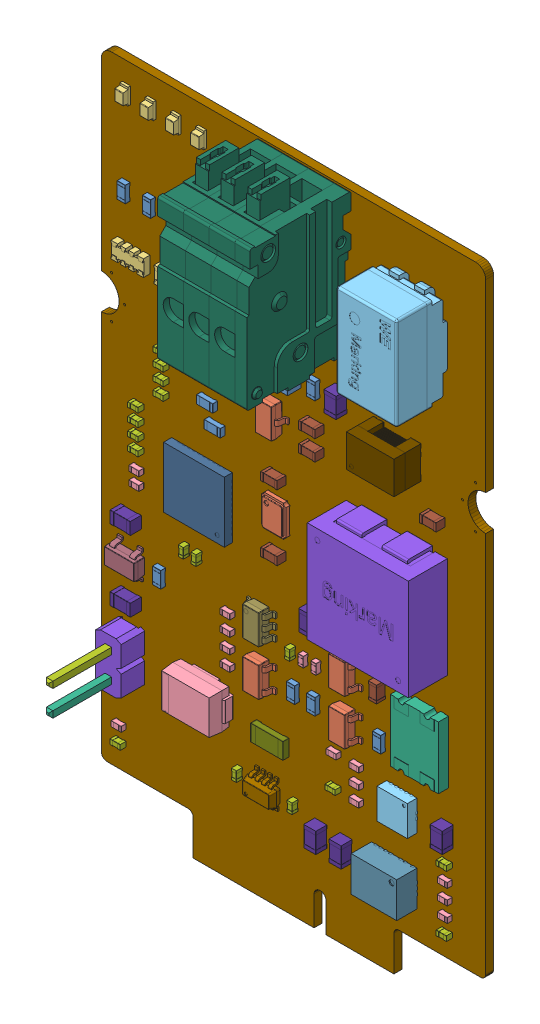
SolidWorks assembly spe-sink, configuration Default. Lengths in mm.
Overall size (38 67.08 13.5).
184 component instances, 27 part files, 0 mates.
Components (placement in the parent):
- spe-sink.step-1: spe-sink.step [Default] at origin size (38 67.08 13.5)
  - RESC1608X50.step-1: RESC1608X50.step [Default] at (121.25 -57.5 0.83) x (0 -1 0) z (0 0 1) size (1.6 0.8 0.5)
    - COMPOUND.step-1: COMPOUND.step [Default] at origin size (1.6 0.8 0.5)
  - RESC1608X50.step-2: RESC1608X50.step [Default] at (105 -50 0.83) x (0 -1 0) z (0 0 1) size (1.6 0.8 0.5)
    - COMPOUND.step-1: COMPOUND.step [Default] at origin size (1.6 0.8 0.5)
  - RESC1608X50.step-3: RESC1608X50.step [Default] at (107.5 -50 0.83) x (0 -1 0) z (0 0 1) size (1.6 0.8 0.5)
    - COMPOUND.step-1: COMPOUND.step [Default] at origin size (1.6 0.8 0.5)
  - SOT95P240X110-3L16.step-1: SOT95P240X110-3L16.step [Default] at (116 -84.5 0.83) size (2.84 3.01 1.19)
    - COMPOUND-0.step-1: COMPOUND-0.step [Default] at origin size (2.84 3.01 1.19)
  - R_Array_Concave_4x060.step-1: R_Array_Concave_4x060.step [Default] at (103.25 -55.25 0.83) x (1 0 0) z (0 -1 0) size (3.2 0.65 1.6)
    - SOLID.step-1: SOLID.step [Default] at origin size (3.2 0.65 1.6)
  - RESC1005X40.step-1: RESC1005X40.step [Default] at (112.75 -85.5 0.83) x (-1 0 0) z (0 0 1) size (1 0.5 0.5)
    - COMPOUND-1.step-1: COMPOUND-1.step [Default] at origin size (1 0.5 0.5)
  - WE-SL2.step-1: WE-SL2.step [Default] at (131.25 -47.5 0.83) x (0 -1 0) z (0 0 1) size (9.2 6 5)
    - COMPOUND-2.step-1: COMPOUND-2.step [Default] at origin size (9.2 6 5)
  - RESC1005X40.step-2: RESC1005X40.step [Default] at (134.25 -94.75 0.83) size (1 0.5 0.5)
    - COMPOUND-1.step-1: COMPOUND-1.step [Default] at origin size (1 0.5 0.5)
  - CD-HD2xL.step-1: CD-HD2xL.step [Default] at (132 -82.25 1.33) x (0 1 0) z (-1 0 0) size (6.15 1.07 4.75)
    - COMPOUND-3.step-1: COMPOUND-3.step [Default] at origin size (6.15 1.07 4.75)
  - RESC1005X40.step-3: RESC1005X40.step [Default] at (111.975 -61.75 0.83) x (0 -1 0) z (0 0 1) size (1 0.5 0.5)
    - COMPOUND-1.step-1: COMPOUND-1.step [Default] at origin size (1 0.5 0.5)
  - CAPC1005X60.step-1: CAPC1005X60.step [Default] at (106.25 -65.5 0.83) x (-1 0 0) z (0 0 1) size (1 0.5 0.6)
    - COMPOUND-4.step-1: COMPOUND-4.step [Default] at origin size (1 0.5 0.6)
  - RESC1608X50.step-4: RESC1608X50.step [Default] at (119.25 -84.5 0.83) x (0 -1 0) z (0 0 1) size (1.6 0.8 0.5)
    - COMPOUND.step-1: COMPOUND.step [Default] at origin size (1.6 0.8 0.5)
  - WE-MCRI-1040.step-1: WE-MCRI-1040.step [Default] at (129.25 -70.75 0.83) x (0 1 0) z (0 0 1) size (10.7 10 4.12)
    - COMPOUND-5.step-1: COMPOUND-5.step [Default] at origin size (10.7 10 4.12)
  - RESC1005X40.step-4: RESC1005X40.step [Default] at (103.75 -73.25 0.83) size (1 0.5 0.5)
    - COMPOUND-1.step-1: COMPOUND-1.step [Default] at origin size (1 0.5 0.5)
  - SOT23_8P65_280X145L45X30.step-1: SOT23_8P65_280X145L45X30.step [Default] at (116.5 -94.25 0.83) size (2.94 2.8 1.2)
    - COMPOUND-6.step-1: COMPOUND-6.step [Default] at origin size (2.94 2.8 1.2)
  - CAPC1005X60.step-2: CAPC1005X60.step [Default] at (106.25 -64.25 0.83) x (-1 0 0) z (0 0 1) size (1 0.5 0.6)
    - COMPOUND-4.step-1: COMPOUND-4.step [Default] at origin size (1 0.5 0.6)
  - QFN50P600X600X100-40.step-1: QFN50P600X600X100-40.step [Default] at (110 -72 0.83) x (0 1 0) z (1 0 0) size (6 0.8 6)
    - COMPOUND-7.step-1: COMPOUND-7.step [Default] at origin size (6 0.8 6)
  - CAPC1005X60.step-3: CAPC1005X60.step [Default] at (103.75 -69 0.83) x (-1 0 0) z (0 0 1) size (1 0.5 0.6)
    - COMPOUND-4.step-1: COMPOUND-4.step [Default] at origin size (1 0.5 0.6)
  - RESC1608X50.step-5: RESC1608X50.step [Default] at (111.5 -65.75 0.83) x (-1 0 0) z (0 0 1) size (1.6 0.8 0.5)
    - COMPOUND.step-1: COMPOUND.step [Default] at origin size (1.6 0.8 0.5)
  - CAPC1608X90.step-1: CAPC1608X90.step [Default] at (121.25 -60.75 0.83) x (-1 0 0) z (0 0 1) size (1.6 0.8 0.9)
    - COMPOUND-8.step-1: COMPOUND-8.step [Default] at origin size (1.6 0.8 0.9)
  - RESC1005X40.step-5: RESC1005X40.step [Default] at (112.75 -82.5 0.83) x (-1 0 0) z (0 0 1) size (1 0.5 0.5)
    - COMPOUND-1.step-1: COMPOUND-1.step [Default] at origin size (1 0.5 0.5)
  - RESC1005X40.step-6: RESC1005X40.step [Default] at (120.25 -81.25 0.83) x (0 -1 0) z (0 0 1) size (1 0.5 0.5)
    - COMPOUND-1.step-1: COMPOUND-1.step [Default] at origin size (1 0.5 0.5)
  - CAPC1005X60.step-4: CAPC1005X60.step [Default] at (106.25 -61.75 0.83) x (-1 0 0) z (0 0 1) size (1 0.5 0.6)
    - COMPOUND-4.step-1: COMPOUND-4.step [Default] at origin size (1 0.5 0.6)
  - CAPC1608X90.step-2: CAPC1608X90.step [Default] at (117.5 -67 0.83) size (1.6 0.8 0.9)
    - COMPOUND-8.step-1: COMPOUND-8.step [Default] at origin size (1.6 0.8 0.9)
  - SOT95P240X110-6L16.step-1: SOT95P240X110-6L16.step [Default] at (116 -80 0.83) x (-1 0 0) z (0 0 1) size (2.85 3.01 1.19)
    - COMPOUND-9.step-1: COMPOUND-9.step [Default] at origin size (2.85 3.01 1.19)
  - RESC1005X40.step-7: RESC1005X40.step [Default] at (125.5 -90.75 0.83) x (-1 0 0) z (0 0 1) size (1 0.5 0.5)
    - COMPOUND-1.step-1: COMPOUND-1.step [Default] at origin size (1 0.5 0.5)
  - RESC1608X50.step-6: RESC1608X50.step [Default] at (121.25 -84.5 0.83) x (0 1 0) z (0 0 1) size (1.6 0.8 0.5)
    - COMPOUND.step-1: COMPOUND.step [Default] at origin size (1.6 0.8 0.5)
  - CAPC1608X90.step-3: CAPC1608X90.step [Default] at (127.75 -80 0.83) x (0 1 0) z (0 0 1) size (1.6 0.8 0.9)
    - COMPOUND-8.step-1: COMPOUND-8.step [Default] at origin size (1.6 0.8 0.9)
  - SOT95P240X110-5L16.step-1: SOT95P240X110-5L16.step [Default] at (103 -81.25 0.83) x (0 -1 0) z (0 0 1) size (2.84 3.01 1.19)
    - COMPOUND-10.step-1: COMPOUND-10.step [Default] at origin size (2.84 3.01 1.19)
  - RESC1005X40.step-8: RESC1005X40.step [Default] at (102 -96 0.83) size (1 0.5 0.5)
    - COMPOUND-1.step-1: COMPOUND-1.step [Default] at origin size (1 0.5 0.5)
  - QFN-FCMOD-11.step-1: QFN-FCMOD-11.step [Default] at (129 -95.5 0.83) x (0 -1 0) z (-1 0 0) size (3.5 2.05 4.5)
    - SOLID-11.step-1: SOLID-11.step [Default] at origin size (3.5 2.05 4.5)
  - CAPC1005X60.step-5: CAPC1005X60.step [Default] at (109.75 -77.75 0.83) x (0 -1 0) z (0 0 1) size (1 0.5 0.6)
    - COMPOUND-4.step-1: COMPOUND-4.step [Default] at origin size (1 0.5 0.6)
  - CUI_TBL009-254-03GY-2OR.step-1: CUI_TBL009-254-03GY-2OR.step [Default] at (124.74 -53.03 0.83) x (-1 0 0) z (0 1 0) size (9.12 13.5 16.11)
    - COMPOUND-12.step-1: COMPOUND-12.step [Default] at origin size (9.12 13.5 16.11)
  - CAPC1005X60.step-6: CAPC1005X60.step [Default] at (134.25 -91.75 0.83) size (1 0.5 0.6)
    - COMPOUND-4.step-1: COMPOUND-4.step [Default] at origin size (1 0.5 0.6)
  - CAPC1005X60.step-7: CAPC1005X60.step [Default] at (106.25 -63 0.83) x (-1 0 0) z (0 0 1) size (1 0.5 0.6)
    - COMPOUND-4.step-1: COMPOUND-4.step [Default] at origin size (1 0.5 0.6)
  - RESC3216X60.step-1: RESC3216X60.step [Default] at (117 -89.75 0.83) x (-1 0 0) z (0 0 1) size (3.2 1.6 0.6)
    - COMPOUND-13.step-1: COMPOUND-13.step [Default] at origin size (3.2 1.6 0.6)
  - CAPC2012X110.step-1: CAPC2012X110.step [Default] at (103 -84.75 0.83) size (2 1.2 1.1)
    - COMPOUND-14.step-1: COMPOUND-14.step [Default] at origin size (2 1.2 1.1)
  - RESC1005X40.step-9: RESC1005X40.step [Default] at (112.75 -81 0.83) x (-1 0 0) z (0 0 1) size (1 0.5 0.5)
    - COMPOUND-1.step-1: COMPOUND-1.step [Default] at origin size (1 0.5 0.5)
  - CAPC1005X60.step-8: CAPC1005X60.step [Default] at (108.5 -77.75 0.83) x (0 -1 0) z (0 0 1) size (1 0.5 0.6)
    - COMPOUND-4.step-1: COMPOUND-4.step [Default] at origin size (1 0.5 0.6)
  - R_Array_Concave_4x060.step-2: R_Array_Concave_4x060.step [Default] at (107.5 -55.25 0.83) x (-1 0 0) z (0 1 0) size (3.2 0.65 1.6)
    - SOLID.step-1: SOLID.step [Default] at origin size (3.2 0.65 1.6)
  - RESC1608X50.step-7: RESC1608X50.step [Default] at (110.75 -64 0.83) x (-1 0 0) z (0 0 1) size (1.6 0.8 0.5)
    - COMPOUND.step-1: COMPOUND.step [Default] at origin size (1.6 0.8 0.5)
  - WE-STST.step-1: WE-STST.step [Default] at (129.26 -58.85 1.58) size (4.71 3.23 2.84)
    - COMPOUND-15.step-1: COMPOUND-15.step [Default] at origin size (4.71 3.23 2.84)
  - CAPC3216X135.step-1: CAPC3216X135.step [Default] at (119 -56.75 0.83) x (0 1 0) z (0 0 1) size (3.2 1.6 1.35)
    - COMPOUND-16.step-1: COMPOUND-16.step [Default] at origin size (3.2 1.6 1.35)
  - SOT95P240X110-3L16.step-2: SOT95P240X110-3L16.step [Default] at (117.25 -61.75 0.83) x (-1 0 0) z (0 0 1) size (2.84 3.01 1.19)
    - COMPOUND-0.step-1: COMPOUND-0.step [Default] at origin size (2.84 3.01 1.19)
  - RESC1608X50.step-8: RESC1608X50.step [Default] at (110 -50 0.83) x (0 1 0) z (0 0 1) size (1.6 0.8 0.5)
    - COMPOUND.step-1: COMPOUND.step [Default] at origin size (1.6 0.8 0.5)
  - CAPC1005X60.step-9: CAPC1005X60.step [Default] at (123.25 -90.75 0.83) size (1 0.5 0.6)
    - COMPOUND-4.step-1: COMPOUND-4.step [Default] at origin size (1 0.5 0.6)
  - RESC1608X50.step-9: RESC1608X50.step [Default] at (113.75 -57.5 0.83) x (0 -1 0) z (0 0 1) size (1.6 0.8 0.5)
    - COMPOUND.step-1: COMPOUND.step [Default] at origin size (1.6 0.8 0.5)
  - OSCCC320X250X60L90X100.step-1: OSCCC320X250X60L90X100.step [Default] at (117.5 -70.25 0.83) x (0 -1 0) z (0 0 1) size (3.1 2.4 0.6)
    - COMPOUND-17.step-1: COMPOUND-17.step [Default] at origin size (3.1 2.4 0.6)
  - RESC1005X40.step-10: RESC1005X40.step [Default] at (112.75 -84 0.83) size (1 0.5 0.5)
    - COMPOUND-1.step-1: COMPOUND-1.step [Default] at origin size (1 0.5 0.5)
  - SOT95P240X110-3L16.step-3: SOT95P240X110-3L16.step [Default] at (124.5 -80 0.83) size (2.84 3.01 1.19)
    - COMPOUND-0.step-1: COMPOUND-0.step [Default] at origin size (2.84 3.01 1.19)
  - RESC1005X40.step-11: RESC1005X40.step [Default] at (110.75 -61.75 0.83) x (0 -1 0) z (0 0 1) size (1 0.5 0.5)
    - COMPOUND-1.step-1: COMPOUND-1.step [Default] at origin size (1 0.5 0.5)
  - CAPC1005X60.step-10: CAPC1005X60.step [Default] at (103.75 -67.75 0.83) x (-1 0 0) z (0 0 1) size (1 0.5 0.6)
    - COMPOUND-4.step-1: COMPOUND-4.step [Default] at origin size (1 0.5 0.6)
  - CAPC1608X90.step-4: CAPC1608X90.step [Default] at (121.25 -62.75 0.83) x (-1 0 0) z (0 0 1) size (1.6 0.8 0.9)
    - COMPOUND-8.step-1: COMPOUND-8.step [Default] at origin size (1.6 0.8 0.9)
  - RESC1005X40.step-12: RESC1005X40.step [Default] at (125.5 -89.25 0.83) x (-1 0 0) z (0 0 1) size (1 0.5 0.5)
    - COMPOUND-1.step-1: COMPOUND-1.step [Default] at origin size (1 0.5 0.5)
  - CAPC1005X60.step-11: CAPC1005X60.step [Default] at (134.25 -97.75 0.83) size (1 0.5 0.6)
    - COMPOUND-4.step-1: COMPOUND-4.step [Default] at origin size (1 0.5 0.6)
  - LEDC1608X80L40.step-1: LEDC1608X80L40.step [Default] at (110 -41.75 0.93) x (0 -1 0) z (-1 0 0) size (1.61 0.75 0.82)
    - COMPOUND-18.step-1: COMPOUND-18.step [Default] at origin size (1.61 0.75 0.82)
  - RESC1608X50.step-10: RESC1608X50.step [Default] at (121.3 -73.5 0.83) x (0 -1 0) z (0 0 1) size (1.6 0.8 0.5)
    - COMPOUND.step-1: COMPOUND.step [Default] at origin size (1.6 0.8 0.5)
  - D_SMB.step-1: D_SMB.step [Default] at (110.5 -89 0.83) size (5.3 3.55 2.15)
    - SOLID-19.step-1: SOLID-19.step [Default] at origin size (5.3 3.55 2.15)
  - CAPC2012X110.step-2: CAPC2012X110.step [Default] at (134.25 -89.25 0.83) x (0 1 0) z (0 0 1) size (2 1.2 1.1)
    - COMPOUND-14.step-1: COMPOUND-14.step [Default] at origin size (2 1.2 1.1)
  - CAPC1608X90.step-5: CAPC1608X90.step [Default] at (133.225 -62.75 0.83) size (1.6 0.8 0.9)
    - COMPOUND-8.step-1: COMPOUND-8.step [Default] at origin size (1.6 0.8 0.9)
  - CAPC2012X110.step-3: CAPC2012X110.step [Default] at (121.25 -77.25 0.83) x (0 -1 0) z (0 0 1) size (2 1.2 1.1)
    - COMPOUND-14.step-1: COMPOUND-14.step [Default] at origin size (2 1.2 1.1)
  - CAPC2012X110.step-4: CAPC2012X110.step [Default] at (123.75 -57.25 0.83) x (0 1 0) z (0 0 1) size (2 1.2 1.1)
    - COMPOUND-14.step-1: COMPOUND-14.step [Default] at origin size (2 1.2 1.1)
  - LEDC1608X80L40.step-2: LEDC1608X80L40.step [Default] at (102.5 -41.75 0.93) x (0 -1 0) z (-1 0 0) size (1.61 0.75 0.82)
    - COMPOUND-18.step-1: COMPOUND-18.step [Default] at origin size (1.61 0.75 0.82)
  - LEDC1608X80L40.step-3: LEDC1608X80L40.step [Default] at (105 -41.75 0.93) x (0 -1 0) z (-1 0 0) size (1.61 0.75 0.82)
    - COMPOUND-18.step-1: COMPOUND-18.step [Default] at origin size (1.61 0.75 0.82)
  - CAPC3216X135.step-2: CAPC3216X135.step [Default] at (116.25 -56.75 0.83) x (0 -1 0) z (0 0 1) size (3.2 1.6 1.35)
    - COMPOUND-16.step-1: COMPOUND-16.step [Default] at origin size (3.2 1.6 1.35)
  - CAPC1005X60.step-12: CAPC1005X60.step [Default] at (119.25 -94.25 0.83) x (0 -1 0) z (0 0 1) size (1 0.5 0.6)
    - COMPOUND-4.step-1: COMPOUND-4.step [Default] at origin size (1 0.5 0.6)
  - RESC1005X40.step-13: RESC1005X40.step [Default] at (123.25 -87.75 0.83) x (-1 0 0) z (0 0 1) size (1 0.5 0.5)
    - COMPOUND-1.step-1: COMPOUND-1.step [Default] at origin size (1 0.5 0.5)
  - RESC1005X40.step-14: RESC1005X40.step [Default] at (125.5 -87.75 0.83) x (-1 0 0) z (0 0 1) size (1 0.5 0.5)
    - COMPOUND-1.step-1: COMPOUND-1.step [Default] at origin size (1 0.5 0.5)
  - RESC1005X40.step-15: RESC1005X40.step [Default] at (103.75 -74.5 0.83) size (1 0.5 0.5)
    - COMPOUND-1.step-1: COMPOUND-1.step [Default] at origin size (1 0.5 0.5)
  - SOT95P240X110-3L16.step-4: SOT95P240X110-3L16.step [Default] at (124.5 -84.5 0.83) size (2.84 3.01 1.19)
    - COMPOUND-0.step-1: COMPOUND-0.step [Default] at origin size (2.84 3.01 1.19)
  - CAPC1005X60.step-13: CAPC1005X60.step [Default] at (103.75 -71.5 0.83) x (-1 0 0) z (0 0 1) size (1 0.5 0.6)
    - COMPOUND-4.step-1: COMPOUND-4.step [Default] at origin size (1 0.5 0.6)
  - CAPC1005X60.step-14: CAPC1005X60.step [Default] at (119 -81.25 0.83) x (0 -1 0) z (0 0 1) size (1 0.5 0.6)
    - COMPOUND-4.step-1: COMPOUND-4.step [Default] at origin size (1 0.5 0.6)
  - RESC1005X40.step-16: RESC1005X40.step [Default] at (109.5 -61.75 0.83) x (0 -1 0) z (0 0 1) size (1 0.5 0.5)
    - COMPOUND-1.step-1: COMPOUND-1.step [Default] at origin size (1 0.5 0.5)
  - SON50P300X300X90-11T240X165N.step-1: SON50P300X300X90-11T240X165N.step [Default] at (129.75 -89.25 0.83) x (0 -1 0) z (-1 0 0) size (3 1 3)
    - COMPOUND-20.step-1: COMPOUND-20.step [Default] at origin size (3 1 3)
  - CAPC1005X60.step-15: CAPC1005X60.step [Default] at (102 -97.5 0.83) x (-1 0 0) z (0 0 1) size (1 0.5 0.6)
    - COMPOUND-4.step-1: COMPOUND-4.step [Default] at origin size (1 0.5 0.6)
  - CAPC1005X60.step-16: CAPC1005X60.step [Default] at (113.75 -94.25 0.83) x (0 1 0) z (0 0 1) size (1 0.5 0.6)
    - COMPOUND-4.step-1: COMPOUND-4.step [Default] at origin size (1 0.5 0.6)
  - RESC1005X40.step-17: RESC1005X40.step [Default] at (134.25 -96.25 0.83) x (-1 0 0) z (0 0 1) size (1 0.5 0.5)
    - COMPOUND-1.step-1: COMPOUND-1.step [Default] at origin size (1 0.5 0.5)
  - RESC1608X50.step-11: RESC1608X50.step [Default] at (102.5 -50 0.83) x (0 -1 0) z (0 0 1) size (1.6 0.8 0.5)
    - COMPOUND.step-1: COMPOUND.step [Default] at origin size (1.6 0.8 0.5)
  - LEDC1608X80L40.step-4: LEDC1608X80L40.step [Default] at (107.5 -41.75 0.93) x (0 -1 0) z (-1 0 0) size (1.61 0.75 0.82)
    - COMPOUND-18.step-1: COMPOUND-18.step [Default] at origin size (1.61 0.75 0.82)
  - CAPC2012X110.step-5: CAPC2012X110.step [Default] at (124.25 -95.5 0.83) x (0 -1 0) z (0 0 1) size (2 1.2 1.1)
    - COMPOUND-14.step-1: COMPOUND-14.step [Default] at origin size (2 1.2 1.1)
  - CAPC1005X60.step-17: CAPC1005X60.step [Default] at (103.75 -70.25 0.83) x (-1 0 0) z (0 0 1) size (1 0.5 0.6)
    - COMPOUND-4.step-1: COMPOUND-4.step [Default] at origin size (1 0.5 0.6)
  - RESC1608X50.step-12: RESC1608X50.step [Default] at (106 -81.25 0.83) x (0 -1 0) z (0 0 1) size (1.6 0.8 0.5)
    - COMPOUND.step-1: COMPOUND.step [Default] at origin size (1.6 0.8 0.5)
  - CAPC2012X110.step-6: CAPC2012X110.step [Default] at (103 -77.75 0.83) size (2 1.2 1.1)
    - COMPOUND-14.step-1: COMPOUND-14.step [Default] at origin size (2 1.2 1.1)
  - RESC1608X50.step-13: RESC1608X50.step [Default] at (127.75 -84.5 0.83) x (0 -1 0) z (0 0 1) size (1.6 0.8 0.5)
    - COMPOUND.step-1: COMPOUND.step [Default] at origin size (1.6 0.8 0.5)
  - CAPC1608X90.step-6: CAPC1608X90.step [Default] at (117.5 -73.5 0.83) x (-1 0 0) z (0 0 1) size (1.6 0.8 0.9)
    - COMPOUND-8.step-1: COMPOUND-8.step [Default] at origin size (1.6 0.8 0.9)
  - RESC1005X40.step-18: RESC1005X40.step [Default] at (121.5 -81.25 0.83) x (0 1 0) z (0 0 1) size (1 0.5 0.5)
    - COMPOUND-1.step-1: COMPOUND-1.step [Default] at origin size (1 0.5 0.5)
  - CAPC2012X110.step-7: CAPC2012X110.step [Default] at (121.75 -95.5 0.83) x (0 -1 0) z (0 0 1) size (2 1.2 1.1)
    - COMPOUND-14.step-1: COMPOUND-14.step [Default] at origin size (2 1.2 1.1)
  - RESC1005X40.step-19: RESC1005X40.step [Default] at (113.25 -61.75 0.83) x (0 -1 0) z (0 0 1) size (1 0.5 0.5)
    - COMPOUND-1.step-1: COMPOUND-1.step [Default] at origin size (1 0.5 0.5)
  - RESC1005X40.step-20: RESC1005X40.step [Default] at (134.25 -93.25 0.83) size (1 0.5 0.5)
    - COMPOUND-1.step-1: COMPOUND-1.step [Default] at origin size (1 0.5 0.5)
  - 61300211121.step-1: 61300211121.step [Default] at (103 -89.255 1.83) x (0 1 0) z (1 0 0) size (5.08 11.54 2.54)
    - SOLID-21.step-1: SOLID-21.step [Default] at origin size (0.64 11.54 0.64)
    - SOLID-22.step-1: SOLID-22.step [Default] at origin size (0.64 11.54 0.64)
    - SOLID-23.step-1: SOLID-23.step [Default] at origin size (5.08 2.54 2.54)
  - spe-sink PCB.step-1: spe-sink PCB.step [Default] at origin size (38 65 0.78)
